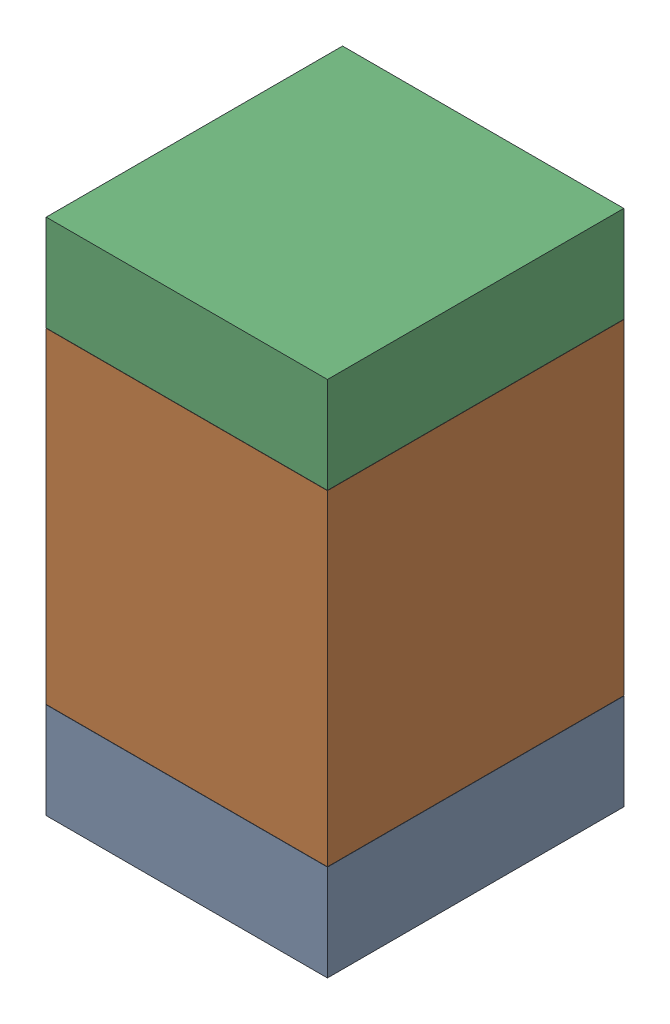
SolidWorks assembly R9, configuration Default. Lengths in mm.
Overall size (0.95 1.75 1).
6 component instances, 2 part files, 0 mates.
Components (placement in the parent):
- 6575495072-1: 6575495072 [Default] at (1.651 19.0995 0) size (0.95 0.32 1)
  - Extruded_6-1: Extruded_6 [Default] at origin size (0.95 0.32 1)
- 6575494912-1: 6575494912 [Default] at (1.651 19.812 0) size (0.95 1.1 1)
  - Extruded_7-1: Extruded_7 [Default] at origin size (0.95 1.1 1)
- 6575495072-2: 6575495072 [Default] at (1.651 20.5245 0) size (0.95 0.32 1)
  - Extruded_6-1: Extruded_6 [Default] at origin size (0.95 0.32 1)
